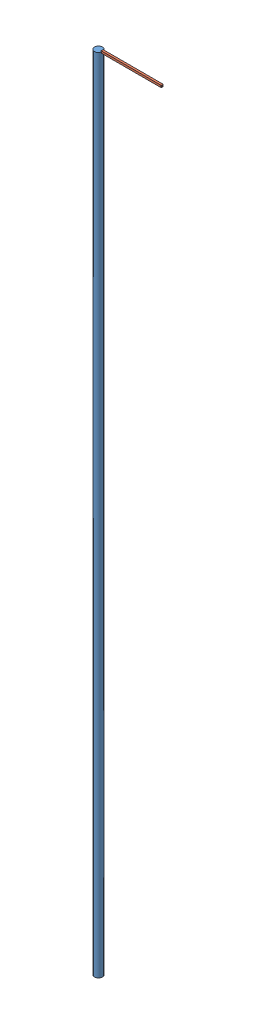
SolidWorks assembly Baugruppe17, configuration Standard. Lengths in mm.
Overall size (845 10012.5 100).
2 component instances, 2 part files, 4 mates.
Components (placement in the parent):
- leiter-Pfeiler-1: leiter-Pfeiler [Standard] at (-2948.5298 -5207.6429 0) size (100 10000 100)
- Teil27^Baugruppe17-1: Teil27^Baugruppe17 [Standard] at (-2948.5298 4792.3571 0) x (-1 0 0) z (0 1 0) size (750 25 25) (virtual)
Mates (geometry in assembly coordinates):
- Platziert1: in place: plane of leiter-Pfeiler-1 through (-2948.5298 4792.3571 0) normal (0 1 0); plane of ? through (0 4792.3571 0) normal (0 1 0); moOrthogonalPlaneRef_w of leiter-Pfeiler-1 through (-2948.5298 4792.3571 0) normal (0 1 0); unknown of ?; plane of leiter-Pfeiler-1 through (-2948.5298 4792.3571 0) normal (0 1 0); line of ? through (-55 0 4792.3571) axis (0 -1 0); plane of leiter-Pfeiler-1 through (-2948.5298 4792.3571 0) normal (0 1 0); unknown of Teil27^Baugruppe17-1
- Deckungsgleich1: coincident aligned: plane of ?; plane of Teil27^Baugruppe17-1
- Deckungsgleich2: coincident aligned: moOrthogonalPlaneRef_w of leiter-Pfeiler-1 through (-2948.5298 4792.3571 0) normal (0 0 1); plane of Teil27^Baugruppe17-1
- Deckungsgleich3: coincident anti-aligned: moOrthogonalPlaneRef_w of leiter-Pfeiler-1 through (-2948.5298 4792.3571 0) normal (1 0 0); plane of Teil27^Baugruppe17-1
